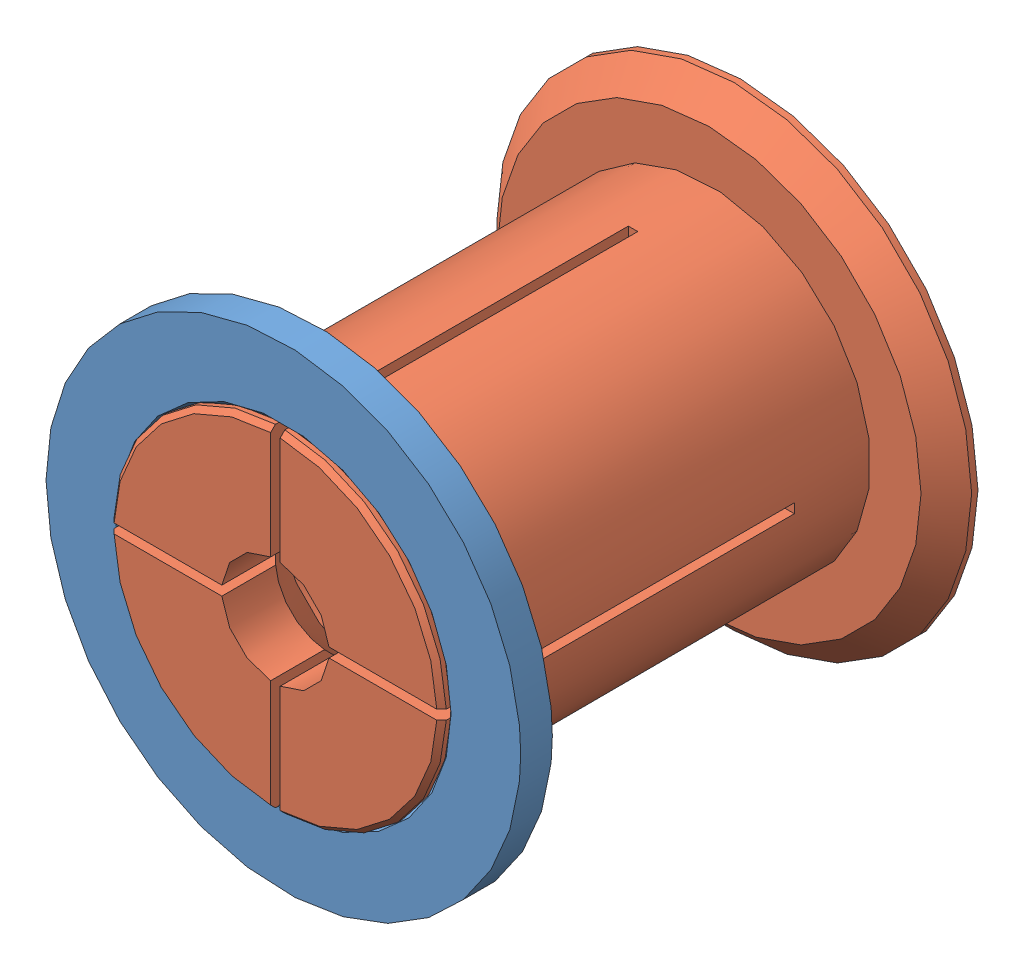
SolidWorks assembly Assem1, configuration Default. Lengths in mm.
Overall size (75 75 73.5).
2 component instances, 2 part files, 2 mates.
Components (placement in the parent):
- 52-62-17-spool-adapter-female-1: 52-62-17-spool-adapter-female [Default] at (9.8401 35.1875 67.3339) size (75 75 5)
- 52-62-17-spool-adapter-male-1: 52-62-17-spool-adapter-male [Default] at (9.8401 35.1875 5.0839) size (75 75 73.5)
Mates (geometry in assembly coordinates):
- Concentric1: concentric: cylinder of 52-62-17-spool-adapter-female-1 through (9.8401 35.1875 67.3339) axis (0 0 1) radius 25.75; cylinder of 52-62-17-spool-adapter-male-1 through (9.8401 35.1875 73.5839) axis (0 0 -1) radius 25.5
- Coincident1: coincident aligned: cone of 52-62-17-spool-adapter-female-1 through (9.8401 35.1875 72.3339) axis (0 0 -1); cone of 52-62-17-spool-adapter-male-1 through (9.8401 35.1875 72.0839) axis (0 0 -1)
